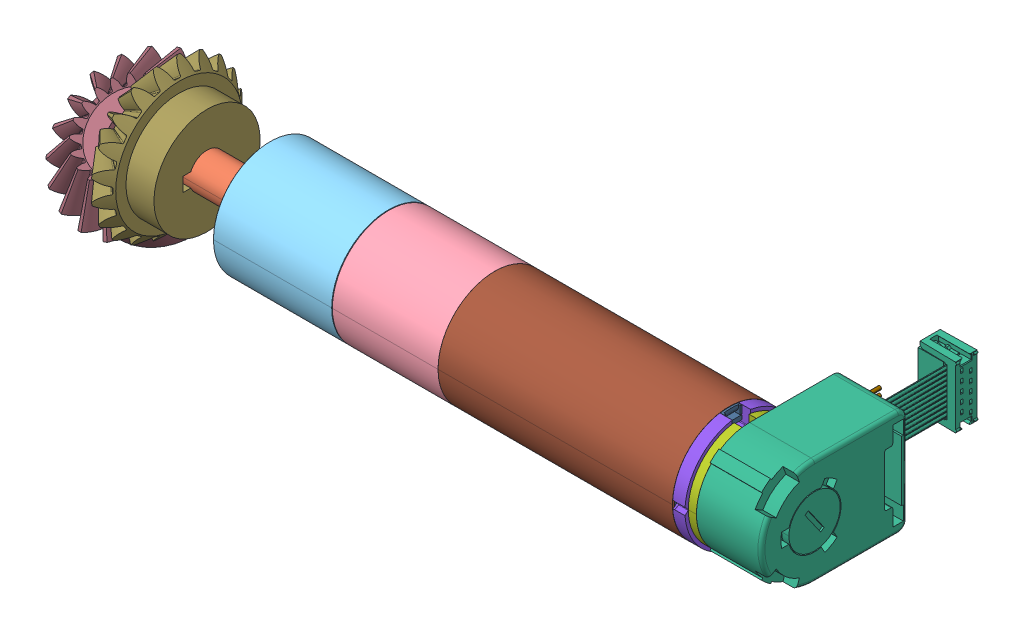
SolidWorks assembly Assem2, configuration Default. Lengths in mm.
Overall size (227.29 80.78 96.88).
16 component instances, 13 part files, 3 mates.
Components (placement in the parent):
- MotorFinal-1: MotorFinal [默认] at (37.8954 93.4939 154.8939) size (188.9 32 73.2)
  - 0_1 (2).stp-1: 0_1 (2).stp [Default] at origin size (188.9 32 73.2)
    - 0.stp-1: 0.stp [Default] at origin size (12 3 3)
    - 0-0.stp-1: 0-0.stp [Default] at origin size (36 10 10.01)
    - 0-1.stp-1: 0-1.stp [Default] at origin size (6 22 22)
    - 0-2.stp-1: 0-2.stp [Default] at origin size (29.95 32 32)
    - 0-3.stp-1: 0-3.stp [Default] at origin size (33.59 32 32)
    - 0-4.stp-1: 0-4.stp [Default] at origin size (20.95 30 72.2)
    - 0-5.stp-1: 0-5.stp [Default] at origin size (2.3 29.7 30)
    - 0-6.stp-1: 0-6.stp [Default] at origin size (3.5 31.47 31.66)
    - 0-7.stp-1: 0-7.stp [Default] at origin size (6.99 3.52 29.03)
    - 0-8.stp-1: 0-8.stp [Default] at origin size (2.9 31.8 31.3)
    - 0-9.stp-1: 0-9.stp [Default] at origin size (66.2 32 32)
- Pinion Gear System-1: Pinion Gear System [Default] at (325.5131 -805.982 1229.2721) x (0.999245 -0.024303 0.030325) z (0 -0.780327 -0.625371) size (55.67 60.71 59.99)
  - straight bevel gear_am-1: straight bevel gear_am [Metric - Straight bevel gear 2M 20GT 20PT 20PA 12FW ---20O30H30MD10S1] at (-367.4444 -1387.6419 -30.0001) x (-0.999245 0.038861 0) z (-0.024303 -0.624899 -0.780327) size (19.85 42.67 42.67)
  - straight bevel pinion_am-1: straight bevel pinion_am [Metric - Straight bevel pinion 2M20PT 20GT 20PA 12FW ---20O35H30MD10N] at (-389.5287 -1386.783 -7.8991) x (0 0 -1) z (0.986616 0.163058 0) size (19.85 42.67 42.67)
Mates (geometry in assembly coordinates):
- Concentric1: concentric: cylinder of MotorFinal-1/0_1 (2).stp-1/0-0.stp-1 through (20.8954 93.4939 154.8939) axis (-1 0 0) radius 5; cylinder of Pinion Gear System-1/straight bevel gear_am-1 through (-42.6013 93.4939 154.8939) axis (1 0 0) radius 5
- Parallel2: parallel: plane of MotorFinal-1/0_1 (2).stp-1/0.stp-1 through (11.8954 93.4939 161.0939) normal (0 0 1); plane of Pinion Gear System-1/straight bevel gear_am-1 through (-42.6013 95.4939 161.6939) normal (0 0 -1)
- Coincident4: coincident aligned: plane of MotorFinal-1/0_1 (2).stp-1/0-0.stp-1 through (2.8954 93.4939 154.8939) normal (-1 0 0); circle of Pinion Gear System-1/straight bevel gear_am-1
